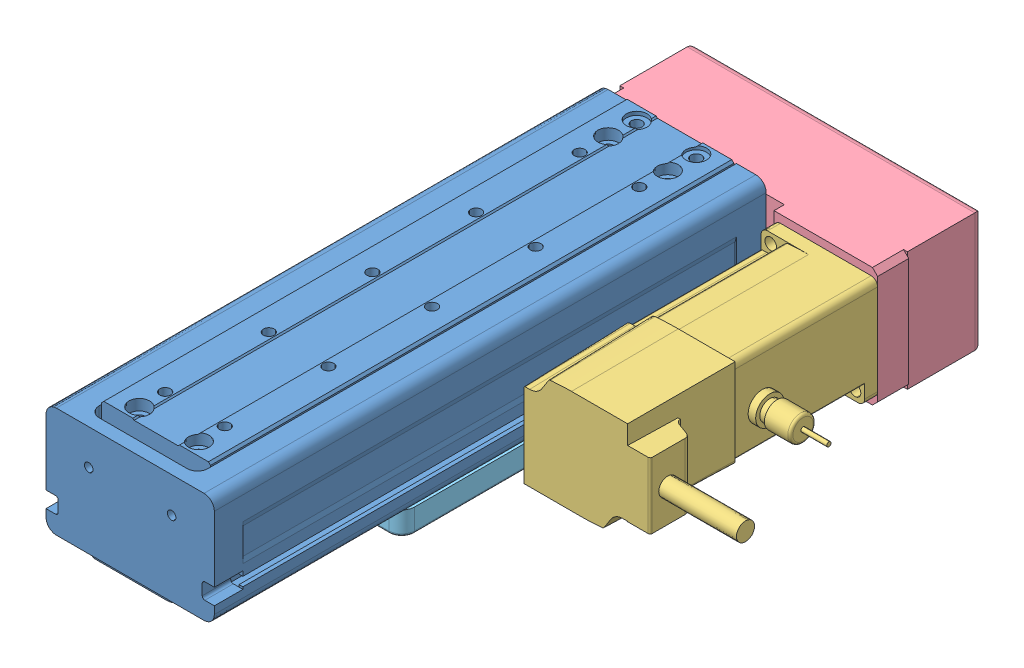
SolidWorks assembly S6M-BL-100W, configuration 默认. Lengths in mm.
Overall size (164.2 56 253.24).
7 component instances, 5 part files, 26 mates.
Components (placement in the parent):
- S6-BL滑块滑轨(CPC)BR-BL-BM共用^S6M-BL-100W-1: S6-BL滑块滑轨(CPC)BR-BL-BM共用^S6M-BL-100W [默认] x (-1 0 0) z (0 0 1) size (65 44.9 219.73) (virtual)
- 传感器^S6M-BL-100W-1: 传感器^S6M-BL-100W [默认] at (-39.25 -39.2 142) x (-1 0 0) z (0 0 -1) size (13.5 27.2 26.1) (virtual)
- 传感器^S6M-BL-100W-2: 传感器^S6M-BL-100W [默认] at (-39.25 -39.2 95.4) x (-1 0 0) z (0 0 -1) size (13.5 27.2 26.1) (virtual)
- 传感器^S6M-BL-100W-3: 传感器^S6M-BL-100W [默认] at (-39.25 -39.2 69.3) x (-1 0 0) z (0 0 -1) size (13.5 27.2 26.1) (virtual)
- 复件 M10^S6M-BL-100W-1: 复件 M10^S6M-BL-100W [默认] at (59.5 -28.9 59) x (0 1 0) z (0 0 1) size (42.1 79.78 121.76) (virtual)
- S5-BL-M10电机安装板^S6M-BL-100W-1: S5-BL-M10电机安装板^S6M-BL-100W [默认] at (23.5 -28.9 -1) x (-1 0 0) z (0 0 -1) size (112 46 41) (virtual)
- S6-BC-滑块组件^S6M-BL-100W-1: S6-BC-滑块组件^S6M-BL-100W [Default] at (0 -1.5 -3.3) x (-1 0 0) z (0 1 0) size (69.5 116 25.18) (virtual)
Mates (geometry in assembly coordinates):
- 重合88: coincident: plane of 传感器^S6M-BL-100W-1 through (-35.5 -37.4 151.9) normal (0 -1 0); plane of 传感器^S6M-BL-100W-2 through (-35.5 -37.4 105.3) normal (0 -1 0)
- 重合92: coincident: plane of 传感器^S6M-BL-100W-2 through (-35.5 -37.4 105.3) normal (0 -1 0); plane of 传感器^S6M-BL-100W-3 through (-35.5 -37.4 79.2) normal (0 -1 0)
- 重合93: coincident: plane of 传感器^S6M-BL-100W-2 through (-35.5 -31.3 79.2) normal (0 0 -1); plane of 传感器^S6M-BL-100W-3 through (-35.5 -31.3 79.2) normal (0 0 1)
- 重合176: coincident: plane of 传感器^S6M-BL-100W-2 through (-35.5 -31.3 79.2) normal (0 0 -1); plane of 传感器^S6M-BL-100W-3 through (-35.5 -31.3 79.2) normal (0 0 1)
- 重合233: coincident: plane of S6-BC-滑块组件^S6M-BL-100W-1; plane of assembly through (0 0 0) normal (1 0 0)
- 重合246: coincident: plane of 传感器^S6M-BL-100W-2 through (-35.5 -37.4 105.3) normal (-1 0 0); plane of 传感器^S6M-BL-100W-3 through (-35.5 -37.4 79.2) normal (-1 0 0)
- 距离1: distance = 56 mm: plane of S6-BC-滑块组件^S6M-BL-100W-1 through (-21 -56 59.2) normal (0 -1 0); plane of S6-BL滑块滑轨(CPC)BR-BL-BM共用^S6M-BL-100W-1 through (0 0 202) normal (0 1 0)
- 重合248: coincident: plane of 传感器^S6M-BL-100W-2 through (-46 -50.3 89.1) normal (-1 0 0); plane of 传感器^S6M-BL-100W-3 through (-46 -50.3 63) normal (-1 0 0)
- 重合249: coincident: plane of 传感器^S6M-BL-100W-1 through (-46 -50.3 135.7) normal (-1 0 0); plane of 传感器^S6M-BL-100W-3 through (-46 -50.3 63) normal (-1 0 0)
- 重合250: coincident: plane of 传感器^S6M-BL-100W-2 through (-32.5 -28.1 89.1) normal (0 1 0); plane of 传感器^S6M-BL-100W-3 through (-32.5 -28.1 63) normal (0 1 0)
- 重合251: coincident: plane of 传感器^S6M-BL-100W-1 through (-32.5 -28.1 135.7) normal (0 1 0); plane of 传感器^S6M-BL-100W-3 through (-32.5 -28.1 63) normal (0 1 0)
- 重合271: coincident: plane of S6-BL滑块滑轨(CPC)BR-BL-BM共用^S6M-BL-100W-1 through (-32.5 -14.4 -67.1611) normal (-1 0 0); plane of 传感器^S6M-BL-100W-1 through (-32.5 -50.3 135.7) normal (1 0 0)
- 距离7: distance = 28.1 mm: plane of 传感器^S6M-BL-100W-1 through (-32.5 -28.1 135.7) normal (0 1 0); plane of S6-BL滑块滑轨(CPC)BR-BL-BM共用^S6M-BL-100W-1 through (0 0 202) normal (0 1 0)
- 重合260: coincident: plane of S6-BL滑块滑轨(CPC)BR-BL-BM共用^S6M-BL-100W-1; plane of S6-BC-滑块组件^S6M-BL-100W-1
- 重合261: coincident: plane of S6-BL滑块滑轨(CPC)BR-BL-BM共用^S6M-BL-100W-1; plane of assembly through (0 0 0) normal (1 0 0)
- 重合262: coincident: plane of S6-BL滑块滑轨(CPC)BR-BL-BM共用^S6M-BL-100W-1; plane of assembly through (0 0 0) normal (0 1 0)
- 重合263: coincident: plane of S6-BL滑块滑轨(CPC)BR-BL-BM共用^S6M-BL-100W-1 through (0 0 0) normal (0 0 1); plane of assembly through (0 0 0) normal (0 0 1)
- 重合264: coincident: plane of S6-BL滑块滑轨(CPC)BR-BL-BM共用^S6M-BL-100W-1 through (0 0 -1) normal (0 0 -1); plane of S5-BL-M10电机安装板^S6M-BL-100W-1 through (-32.5 -5.9 -1) normal (0 0 1)
- 重合265: coincident: plane of S6-BL滑块滑轨(CPC)BR-BL-BM共用^S6M-BL-100W-1 through (-32.5 -14.4 -67.1611) normal (-1 0 0); plane of S5-BL-M10电机安装板^S6M-BL-100W-1 through (-32.5 -51.9 -9) normal (-1 0 0)
- 距离8: distance = 8 mm: plane of S5-BL-M10电机安装板^S6M-BL-100W-1 through (79.5 -51.9 -9) normal (0 -1 0); plane of S6-BL滑块滑轨(CPC)BR-BL-BM共用^S6M-BL-100W-1 through (0 -43.9 -67.1611) normal (0 -1 0)
- 重合267: coincident: plane of 复件 M10^S6M-BL-100W-1 through (60.9978 49.0984 3) normal (0 0 -1); plane of S5-BL-M10电机安装板^S6M-BL-100W-1 through (23.5 -28.9 3) normal (0 0 1)
- 同心1: concentric: cylinder of 复件 M10^S6M-BL-100W-1 through (59.5 -28.9 -22) axis (0 0 1) radius 4; cylinder of S5-BL-M10电机安装板^S6M-BL-100W-1 through (59.5 -28.9 3) axis (0 0 -1) radius 15.1
- 平行1: parallel: plane of 复件 M10^S6M-BL-100W-1 through (79.5 -28.9 59) normal (1 0 0); plane of S5-BL-M10电机安装板^S6M-BL-100W-1 through (79.5 -51.9 -9) normal (1 0 0)
- 距离11: distance = 70 mm: plane of 传感器^S6M-BL-100W-1 through (-46 -28.1 142) normal (0 0 1); plane of S6-BL滑块滑轨(CPC)BR-BL-BM共用^S6M-BL-100W-1 through (0 0 212) normal (0 0 1)
- 距离12: distance = 101 mm: plane of 传感器^S6M-BL-100W-3 through (-46 -28.1 63) normal (0 0 -1); plane of S5-BL-M10电机安装板^S6M-BL-100W-1 through (23.5 -28.9 -38) normal (0 0 -1)
- 宽度1: width: plane of 传感器^S6M-BL-100W-2 through (-46 -28.1 89.1) normal (0 0 -1); plane of 传感器^S6M-BL-100W-3 through (-46 -28.1 69.3) normal (0 0 1); plane of S6-BC-滑块组件^S6M-BL-100W-1 through (-28.75 -49.4 88.7) normal (0 0 1); plane of S6-BC-滑块组件^S6M-BL-100W-1 through (-28.75 -49.4 69.7) normal (0 0 -1)
